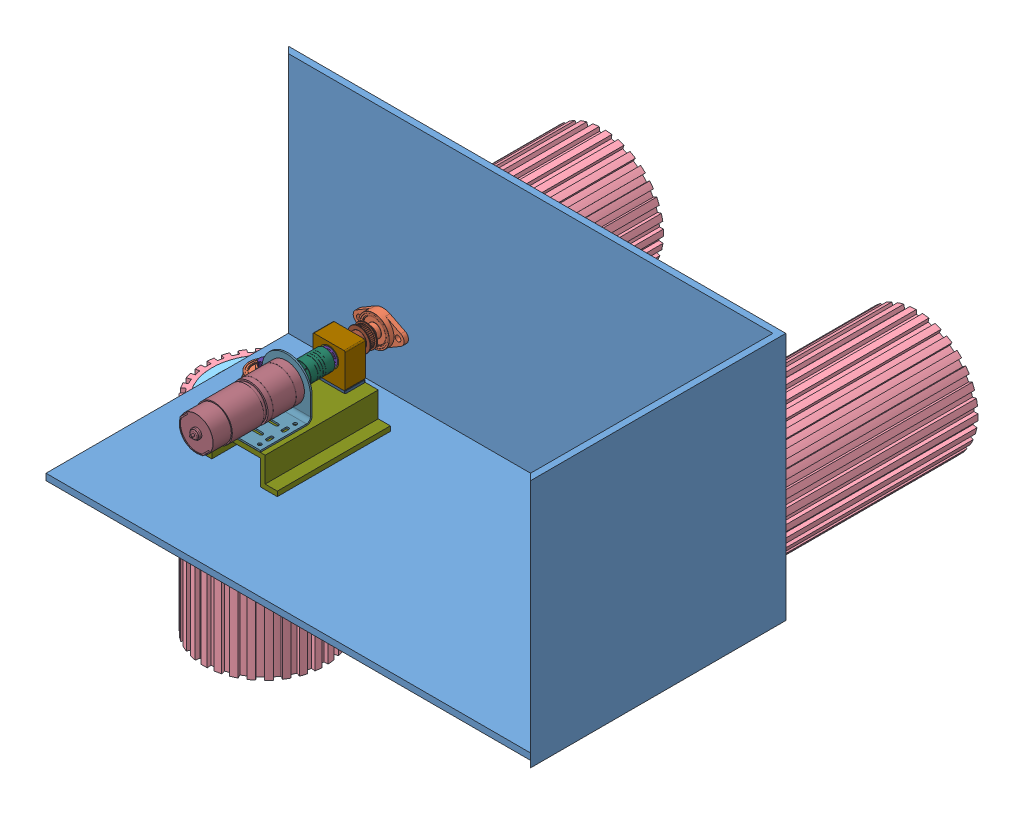
SolidWorks assembly moter in box assemly2, configuration Default. Lengths in mm.
Overall size (646.36 568 580.4).
82 component instances, 17 part files, 9 mates.
Components (placement in the parent):
- box-1: box [Default] at (214.7869 209.4239 556.9442) size (616 308 316)
- wheel without moter subassembley-1: wheel without moter subassembley [Default] at (363.3222 36.9 0) size (173.81 173.65 354)
  - KFL001 block flange ball bearing 12 diameter shaft-1: KFL001 block flange ball bearing 12 diameter shaft [Default] at (58.0648 247.4239 406.9442) x (-0.381567 0.924341 0) z (0.924341 0.381567 0) size (38 16 63)
  - wheel shaft-1: wheel shaft [Default] at (58.0648 247.4239 234.5442) x (0.174278 -0.984697 0) z (-0.984697 -0.174278 0) size (12 354 12)
  - wheel rubber-1: wheel rubber [Default] at (58.0648 247.4239 134.5442) x (-0.174278 0.984697 0) z (0.984697 0.174278 0) size (149.8 250 150)
  - wheel rim-1: wheel rim [Default] at (58.0648 247.4239 134.5442) x (-0.174278 0.984697 0) z (0.984697 0.174278 0) size (130 250 130)
  - Bearing House v1.step-1: Bearing House v1.step [Default] at (58.0648 227.9239 462.9398) x (-1 0 0) z (0 1 0) size (40 25 45.94)
    - SKF_61901-2Z.step-1: SKF_61901-2Z.step [Default] at (0 -8 19.5) x (0 -1 0) z (0 0 1) size (6 24 24)
      - SKF_61901-2Z_ball1.step-1: SKF_61901-2Z_ball1.step [Default] at (6 16.2812 -5.2901) x (-1 0 0) z (0 0 1) size (3.18 3.17 3.17)
      - SKF_61901-2Z_ball1.step-2: SKF_61901-2Z_ball1.step [Default] at (6 11.7812 -8.5595) x (-1 0 0) z (0 0 1) size (3.18 3.17 3.17)
      - SKF_61901-2Z_ball1.step-3: SKF_61901-2Z_ball1.step [Default] at (6 6.2188 -8.5595) x (-1 0 0) z (0 0 1) size (3.18 3.17 3.17)
      - SKF_61901-2Z_ball1.step-4: SKF_61901-2Z_ball1.step [Default] at (6 1.7188 -5.2901) x (-1 0 0) z (0 0 1) size (3.18 3.17 3.17)
      - SKF_61901-2Z_ball1.step-5: SKF_61901-2Z_ball1.step [Default] at (6 0 0) x (-1 0 0) z (0 0 1) size (3.18 3.17 3.17)
      - SKF_61901-2Z_ball1.step-6: SKF_61901-2Z_ball1.step [Default] at (6 1.7188 5.2901) x (-1 0 0) z (0 0 1) size (3.18 3.17 3.17)
      - SKF_61901-2Z_ball1.step-7: SKF_61901-2Z_ball1.step [Default] at (6 6.2188 8.5595) x (-1 0 0) z (0 0 1) size (3.18 3.17 3.17)
      - SKF_61901-2Z_ball1.step-8: SKF_61901-2Z_ball1.step [Default] at (6 11.7812 8.5595) x (-1 0 0) z (0 0 1) size (3.18 3.17 3.17)
      - SKF_61901-2Z_ball1.step-9: SKF_61901-2Z_ball1.step [Default] at (6 16.2812 5.2901) x (-1 0 0) z (0 0 1) size (3.18 3.17 3.17)
      - SKF_61901-2Z_ball1.step-10: SKF_61901-2Z_ball1.step [Default] at (6 18 0) x (-1 0 0) z (0 0 1) size (3.18 3.17 3.17)
      - SKF_61901-2Z_or.step-1: SKF_61901-2Z_or.step [Default] x (1 0 0) z (0 0 -1) size (6 24 24)
      - SKF_61901-2Z_ir.step-1: SKF_61901-2Z_ir.step [Default] x (1 0 0) z (0 0 -1) size (6 21.4 21.4)
    - SKF_61901-2Z.step-2: SKF_61901-2Z.step [Default] at (0 5 19.5) x (0 1 0) z (0 0 1) size (6 24 24)
      - SKF_61901-2Z_ball1.step-1: SKF_61901-2Z_ball1.step [Default] at (6 16.2812 -5.2901) x (-1 0 0) z (0 0 1) size (3.18 3.17 3.17)
      - SKF_61901-2Z_ball1.step-2: SKF_61901-2Z_ball1.step [Default] at (6 11.7812 -8.5595) x (-1 0 0) z (0 0 1) size (3.18 3.17 3.17)
      - SKF_61901-2Z_ball1.step-3: SKF_61901-2Z_ball1.step [Default] at (6 6.2188 -8.5595) x (-1 0 0) z (0 0 1) size (3.18 3.17 3.17)
      - SKF_61901-2Z_ball1.step-4: SKF_61901-2Z_ball1.step [Default] at (6 1.7188 -5.2901) x (-1 0 0) z (0 0 1) size (3.18 3.17 3.17)
      - SKF_61901-2Z_ball1.step-5: SKF_61901-2Z_ball1.step [Default] at (6 0 0) x (-1 0 0) z (0 0 1) size (3.18 3.17 3.17)
      - SKF_61901-2Z_ball1.step-6: SKF_61901-2Z_ball1.step [Default] at (6 1.7188 5.2901) x (-1 0 0) z (0 0 1) size (3.18 3.17 3.17)
      - SKF_61901-2Z_ball1.step-7: SKF_61901-2Z_ball1.step [Default] at (6 6.2188 8.5595) x (-1 0 0) z (0 0 1) size (3.18 3.17 3.17)
      - SKF_61901-2Z_ball1.step-8: SKF_61901-2Z_ball1.step [Default] at (6 11.7812 8.5595) x (-1 0 0) z (0 0 1) size (3.18 3.17 3.17)
      - SKF_61901-2Z_ball1.step-9: SKF_61901-2Z_ball1.step [Default] at (6 16.2812 5.2901) x (-1 0 0) z (0 0 1) size (3.18 3.17 3.17)
      - SKF_61901-2Z_ball1.step-10: SKF_61901-2Z_ball1.step [Default] at (6 18 0) x (-1 0 0) z (0 0 1) size (3.18 3.17 3.17)
      - SKF_61901-2Z_or.step-1: SKF_61901-2Z_or.step [Default] x (1 0 0) z (0 0 -1) size (6 24 24)
      - SKF_61901-2Z_ir.step-1: SKF_61901-2Z_ir.step [Default] x (1 0 0) z (0 0 -1) size (6 21.4 21.4)
    - Universal Bearing Housing.step-1: Universal Bearing Housing.step [Default] at (0 11.0044 14.0358) x (1 0 0) z (0 -1 0) size (40 43 25)
    - Universal Bearing Housing Spacer.step-1: Universal Bearing Housing Spacer.step [Default] at (0 -1.5 -7.4) x (1 0 0) z (0 1 0) size (40 3 25)
  - GT2 40T id 12mm bw 7mm-1: GT2 40T id 12mm bw 7mm [Výchozí] at (58.0648 247.4239 435.4442) x (0.924379 0.381477 0) z (0.381477 -0.924379 0) size (28.2 17 28.2)
  - height extender 25mm-1: height extender 25mm [Default] at (7.0648 186.5239 448.9398) size (102 37 25)
- Wheel with moter assembly-1: Wheel with moter assembly [Default] at (-38.0123 37 0) size (163.26 163.44 510.81)
  - Motor DC PG45-1: Motor DC PG45 [Default] at (70.1664 247.4239 638.3442) x (0.707107 0.707107 0) z (-0.707107 0.707107 0) size (45 146.01 45)
  - Mounting Bracket Motor DC PG45 Orange-1: Mounting Bracket Motor DC PG45 Orange [Default] at (91.7552 243.9192 526.8442) x (-1 0 0) z (0 0 -1) size (60 60 63.93)
  - KFL001 block flange ball bearing 12 diameter shaft-1: KFL001 block flange ball bearing 12 diameter shaft [Default] at (70.1664 247.4239 406.9442) x (-0.034258 0.999413 0) z (0.999413 0.034258 0) size (38 16 63)
  - wheel shaft-1: wheel shaft [Default] at (70.1664 247.4239 234.5442) x (0.995554 -0.094191 0) z (-0.094191 -0.995554 0) size (12 354 12)
  - Shaft_Coupler_6.35x12mm-1: Shaft_Coupler_6.35x12mm [По умолчанию] at (70.1664 247.4239 508.9442) x (0.647293 0.762241 0) z (-0.762241 0.647293 0) size (25.41 30 25.41)
  - wheel rubber-1: wheel rubber [Default] at (70.1664 247.4239 134.5442) x (-0.995554 0.094191 0) z (0.094191 0.995554 0) size (149.8 250 150)
  - wheel rim-1: wheel rim [Default] at (70.1664 247.4239 134.5442) x (-0.995554 0.094191 0) z (0.094191 0.995554 0) size (130 250 130)
  - Bearing House v1.step-1: Bearing House v1.step [Default] at (70.1664 227.9239 462.9398) x (-1 0 0) z (0 1 0) size (40 25 45.94)
    - SKF_61901-2Z.step-1: SKF_61901-2Z.step [Default] at (0 -8 19.5) x (0 -1 0) z (0 0 1) size (6 24 24)
      - SKF_61901-2Z_ball1.step-1: SKF_61901-2Z_ball1.step [Default] at (6 16.2812 -5.2901) x (-1 0 0) z (0 0 1) size (3.18 3.17 3.17)
      - SKF_61901-2Z_ball1.step-2: SKF_61901-2Z_ball1.step [Default] at (6 11.7812 -8.5595) x (-1 0 0) z (0 0 1) size (3.18 3.17 3.17)
      - SKF_61901-2Z_ball1.step-3: SKF_61901-2Z_ball1.step [Default] at (6 6.2188 -8.5595) x (-1 0 0) z (0 0 1) size (3.18 3.17 3.17)
      - SKF_61901-2Z_ball1.step-4: SKF_61901-2Z_ball1.step [Default] at (6 1.7188 -5.2901) x (-1 0 0) z (0 0 1) size (3.18 3.17 3.17)
      - SKF_61901-2Z_ball1.step-5: SKF_61901-2Z_ball1.step [Default] at (6 0 0) x (-1 0 0) z (0 0 1) size (3.18 3.17 3.17)
      - SKF_61901-2Z_ball1.step-6: SKF_61901-2Z_ball1.step [Default] at (6 1.7188 5.2901) x (-1 0 0) z (0 0 1) size (3.18 3.17 3.17)
      - SKF_61901-2Z_ball1.step-7: SKF_61901-2Z_ball1.step [Default] at (6 6.2188 8.5595) x (-1 0 0) z (0 0 1) size (3.18 3.17 3.17)
      - SKF_61901-2Z_ball1.step-8: SKF_61901-2Z_ball1.step [Default] at (6 11.7812 8.5595) x (-1 0 0) z (0 0 1) size (3.18 3.17 3.17)
      - SKF_61901-2Z_ball1.step-9: SKF_61901-2Z_ball1.step [Default] at (6 16.2812 5.2901) x (-1 0 0) z (0 0 1) size (3.18 3.17 3.17)
      - SKF_61901-2Z_ball1.step-10: SKF_61901-2Z_ball1.step [Default] at (6 18 0) x (-1 0 0) z (0 0 1) size (3.18 3.17 3.17)
      - SKF_61901-2Z_or.step-1: SKF_61901-2Z_or.step [Default] x (1 0 0) z (0 0 -1) size (6 24 24)
      - SKF_61901-2Z_ir.step-1: SKF_61901-2Z_ir.step [Default] x (1 0 0) z (0 0 -1) size (6 21.4 21.4)
    - SKF_61901-2Z.step-2: SKF_61901-2Z.step [Default] at (0 5 19.5) x (0 1 0) z (0 0 1) size (6 24 24)
      - SKF_61901-2Z_ball1.step-1: SKF_61901-2Z_ball1.step [Default] at (6 16.2812 -5.2901) x (-1 0 0) z (0 0 1) size (3.18 3.17 3.17)
      - SKF_61901-2Z_ball1.step-2: SKF_61901-2Z_ball1.step [Default] at (6 11.7812 -8.5595) x (-1 0 0) z (0 0 1) size (3.18 3.17 3.17)
      - SKF_61901-2Z_ball1.step-3: SKF_61901-2Z_ball1.step [Default] at (6 6.2188 -8.5595) x (-1 0 0) z (0 0 1) size (3.18 3.17 3.17)
      - SKF_61901-2Z_ball1.step-4: SKF_61901-2Z_ball1.step [Default] at (6 1.7188 -5.2901) x (-1 0 0) z (0 0 1) size (3.18 3.17 3.17)
      - SKF_61901-2Z_ball1.step-5: SKF_61901-2Z_ball1.step [Default] at (6 0 0) x (-1 0 0) z (0 0 1) size (3.18 3.17 3.17)
      - SKF_61901-2Z_ball1.step-6: SKF_61901-2Z_ball1.step [Default] at (6 1.7188 5.2901) x (-1 0 0) z (0 0 1) size (3.18 3.17 3.17)
      - SKF_61901-2Z_ball1.step-7: SKF_61901-2Z_ball1.step [Default] at (6 6.2188 8.5595) x (-1 0 0) z (0 0 1) size (3.18 3.17 3.17)
      - SKF_61901-2Z_ball1.step-8: SKF_61901-2Z_ball1.step [Default] at (6 11.7812 8.5595) x (-1 0 0) z (0 0 1) size (3.18 3.17 3.17)
      - SKF_61901-2Z_ball1.step-9: SKF_61901-2Z_ball1.step [Default] at (6 16.2812 5.2901) x (-1 0 0) z (0 0 1) size (3.18 3.17 3.17)
      - SKF_61901-2Z_ball1.step-10: SKF_61901-2Z_ball1.step [Default] at (6 18 0) x (-1 0 0) z (0 0 1) size (3.18 3.17 3.17)
      - SKF_61901-2Z_or.step-1: SKF_61901-2Z_or.step [Default] x (1 0 0) z (0 0 -1) size (6 24 24)
      - SKF_61901-2Z_ir.step-1: SKF_61901-2Z_ir.step [Default] x (1 0 0) z (0 0 -1) size (6 21.4 21.4)
    - Universal Bearing Housing.step-1: Universal Bearing Housing.step [Default] at (0 11.0044 14.0358) x (1 0 0) z (0 -1 0) size (40 43 25)
    - Universal Bearing Housing Spacer.step-1: Universal Bearing Housing Spacer.step [Default] at (0 -1.5 -7.4) x (1 0 0) z (0 1 0) size (40 3 25)
  - GT2 40T id 12mm bw 7mm-1: GT2 40T id 12mm bw 7mm [Výchozí] at (70.1664 247.4239 435.4442) x (0.924379 0.381477 0) z (0.381477 -0.924379 0) size (28.2 17 28.2)
  - height extender 140mm-1: height extender 140mm [Default] at (19.1664 186.4239 448.9442) size (102 37 140)
- wheel with block flange assembly-1: wheel with block flange assembly [Default] at (-91.0948 94.6445 420.2865) x (1 0 0.000017) z (-0.000017 0 1) size (149.8 290 150)
  - support wheel shaft-1: support wheel shaft [Default] at (42.428 -109.2206 52.657) size (12 290 12)
  - KFL001 block flange ball bearing 12 diameter shaft-1: KFL001 block flange ball bearing 12 diameter shaft [Default] at (42.428 122.7794 52.657) size (38 16 63)
  - wheel assembly 250mm-1: wheel assembly 250mm [Default] at (109.3345 -177.8583 324.9521) x (-1 0 0) z (0 0 -1) size (149.8 250 150)
    - wheel rim-1: wheel rim [Default] at (66.9065 32.6377 272.2951) size (130 250 130)
    - wheel rubber-1: wheel rubber [Default] at (66.9065 32.6377 272.2951) size (149.8 250 150)
Mates (geometry in assembly coordinates):
- Parallel6: parallel anti-aligned: line of box-1 through (-85.2131 217.4239 406.9442) axis (0 0 1); line of wheel without moter subassembley-1/Bearing House v1.step-1/Universal Bearing Housing Spacer.step-1 through (401.3869 254.4239 472.9398) axis (0 0 -1)
- Parallel7: parallel anti-aligned: line of box-1 through (-85.2131 217.4239 706.9442) axis (1 0 0); line of wheel without moter subassembley-1/Bearing House v1.step-1/Universal Bearing Housing Spacer.step-1 through (440.3869 254.4239 473.9398) axis (-1 0 0)
- Coincident18: coincident anti-aligned: plane of box-1 through (214.7869 517.4239 406.9442) normal (0 0 1); plane of wheel without moter subassembley-1/KFL001 block flange ball bearing 12 diameter shaft-1 through (421.3869 284.3239 406.9442) normal (0 0 -1)
- Coincident22: coincident anti-aligned: plane of box-1 through (214.7869 217.4239 556.9442) normal (0 1 0); plane of wheel without moter subassembley-1/height extender 25mm-1 through (391.3869 217.4239 473.9398) normal (0 -1 0)
- Coincident23: coincident anti-aligned: plane of box-1 through (214.7869 217.4239 556.9442) normal (0 1 0); plane of Wheel with moter assembly-1/height extender 140mm-1 through (2.1542 217.4239 588.9442) normal (0 -1 0)
- Coincident24: coincident anti-aligned: plane of box-1 through (214.7869 517.4239 406.9442) normal (0 0 1); plane of Wheel with moter assembly-1/KFL001 block flange ball bearing 12 diameter shaft-1 through (32.1542 284.4239 406.9442) normal (0 0 -1)
- Coincident25: coincident anti-aligned: plane of box-1 through (214.7869 217.4239 556.9442) normal (0 1 0); plane of wheel with block flange assembly-1/KFL001 block flange ball bearing 12 diameter shaft-1 through (-48.6677 217.4239 472.9442) normal (0 -1 0)
- Angle3: planar angle = 0.499688 rad aligned: line of wheel with block flange assembly-1/KFL001 block flange ball bearing 12 diameter shaft-1 through (-65.3447 217.4239 482.0481) axis (0.479152 0 0.877732); line of box-1 through (-85.2131 217.4239 406.9442) axis (0 0 1)
- Distance2: distance = 75 mm: point of wheel with block flange assembly-1/support wheel shaft-1; plane of box-1 through (214.7869 517.4239 398.9442) normal (0 0 -1)
